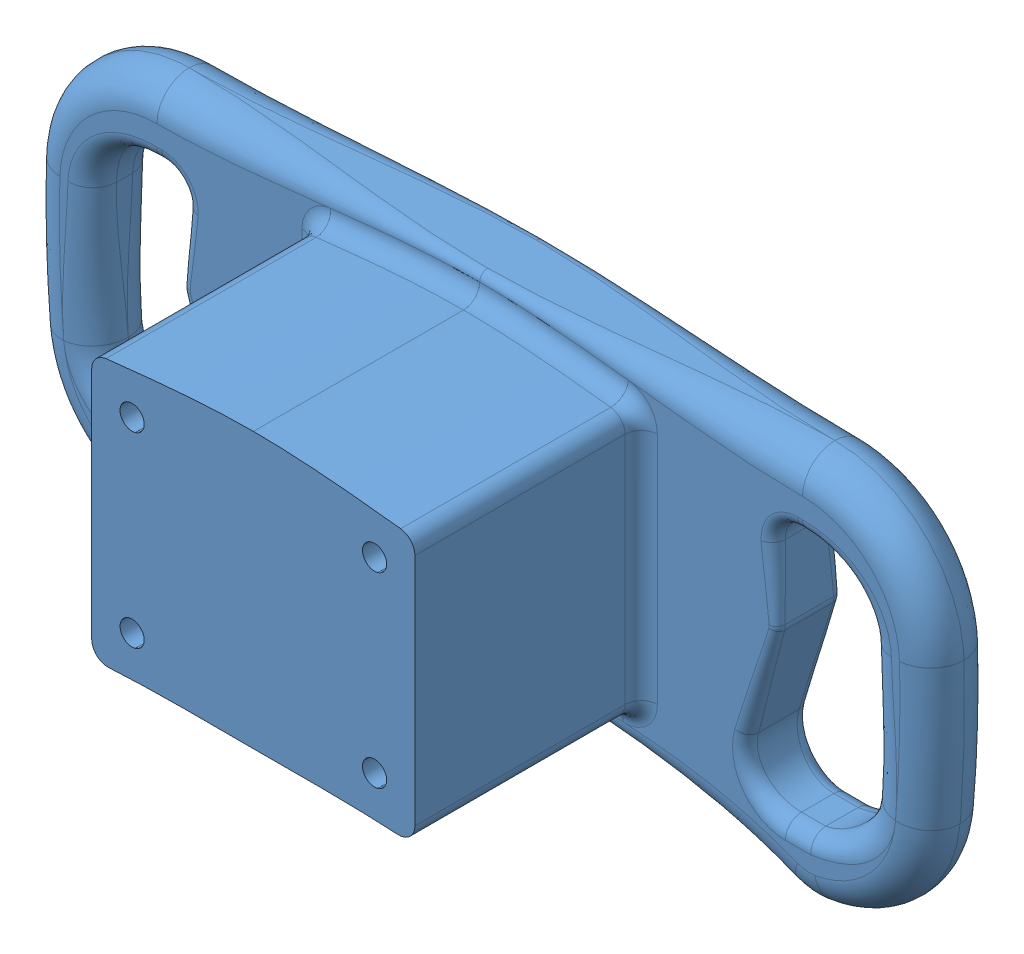
SolidWorks assembly Assem1, configuration Default. Lengths in mm.
Overall size (356.28 152.54 114.94).
2 component instances, 2 part files, 3 mates.
Components (placement in the parent):
- carbon wheel v2-1: carbon wheel v2 [Default] at origin size (356.28 152.54 114.94)
- carbon wheel faceplate v2-2: carbon wheel faceplate v2 [Default] at (-0.0156 34.9229 -12.7) size (212.45 110.1 3.81)
Mates (geometry in assembly coordinates):
- Coincident2: coincident: plane of carbon wheel v2-1 through (103.2588 76.7502 -8.89) normal (0 0 -1); plane of carbon wheel faceplate v2-2 through (-93.6992 61.4722 -8.89) normal (0 0 1)
- Concentric1: concentric: circle of carbon wheel v2-1; circle of carbon wheel faceplate v2-2
- Concentric2: concentric anti-aligned: circle of carbon wheel v2-1; circle of carbon wheel faceplate v2-2
